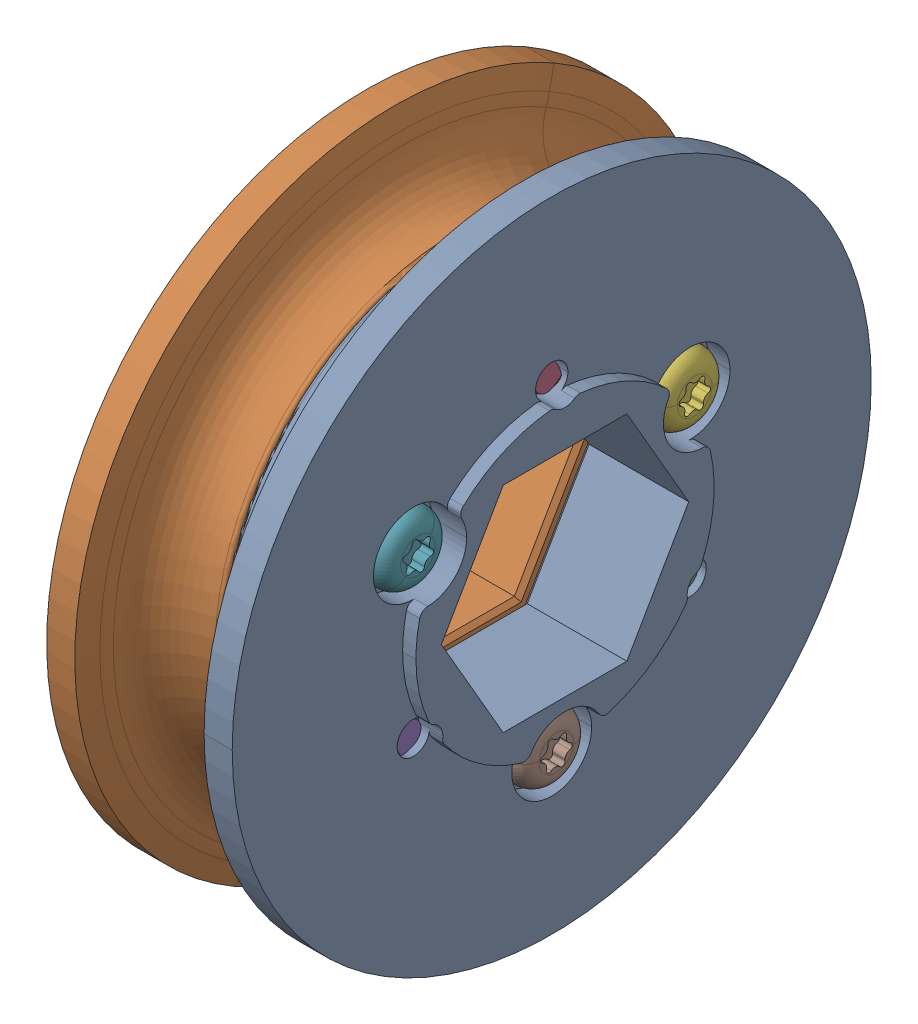
SolidWorks assembly WCP-0096 Rev6-6.step, configuration Default. Lengths in mm.
Overall size (12.65 52.05 52.05).
8 component instances, 2 part files, 0 mates.
Components (placement in the parent):
- WCP-0096-001 Rev6.step-1: WCP-0096-001 Rev6.step [Default] at origin size (7.57 38.1 38.1)
- WCP-0096-001 Rev6.step-2: WCP-0096-001 Rev6.step [Default] x (-1 0 0) z (0 0.866025 -0.5) size (7.57 38.1 38.1)
- WCP-0356 Rev1.step-1: WCP-0356 Rev1.step [Default] at (0.4817 -4.7625 -8.2489) x (0 -0.126969 0.991907) z (0 -0.991907 -0.126969) size (4.06 11.05 4.06)
- WCP-0356 Rev1.step-2: WCP-0356 Rev1.step [Default] at (0.4817 9.525 0) x (0 0.866766 0.498715) z (0 -0.498715 0.866766) size (4.06 11.05 4.06)
- WCP-0356 Rev1.step-3: WCP-0356 Rev1.step [Default] at (0.4817 -4.7625 8.2489) x (0 -0.994015 -0.109248) z (0 0.109248 -0.994015) size (4.06 11.05 4.06)
- WCP-0356 Rev1.step-4: WCP-0356 Rev1.step [Default] at (-0.4817 4.7625 -8.2489) x (0 -0.997555 0.069879) z (0 0.069879 0.997555) size (4.06 11.05 4.06)
- WCP-0356 Rev1.step-5: WCP-0356 Rev1.step [Default] at (-0.4817 4.7625 8.2489) x (0 -0.7202 -0.693767) z (0 -0.693767 0.7202) size (4.06 11.05 4.06)
- WCP-0356 Rev1.step-6: WCP-0356 Rev1.step [Default] at (-0.4817 -9.525 0) x (0 -0.997555 0.069879) z (0 0.069879 0.997555) size (4.06 11.05 4.06)
